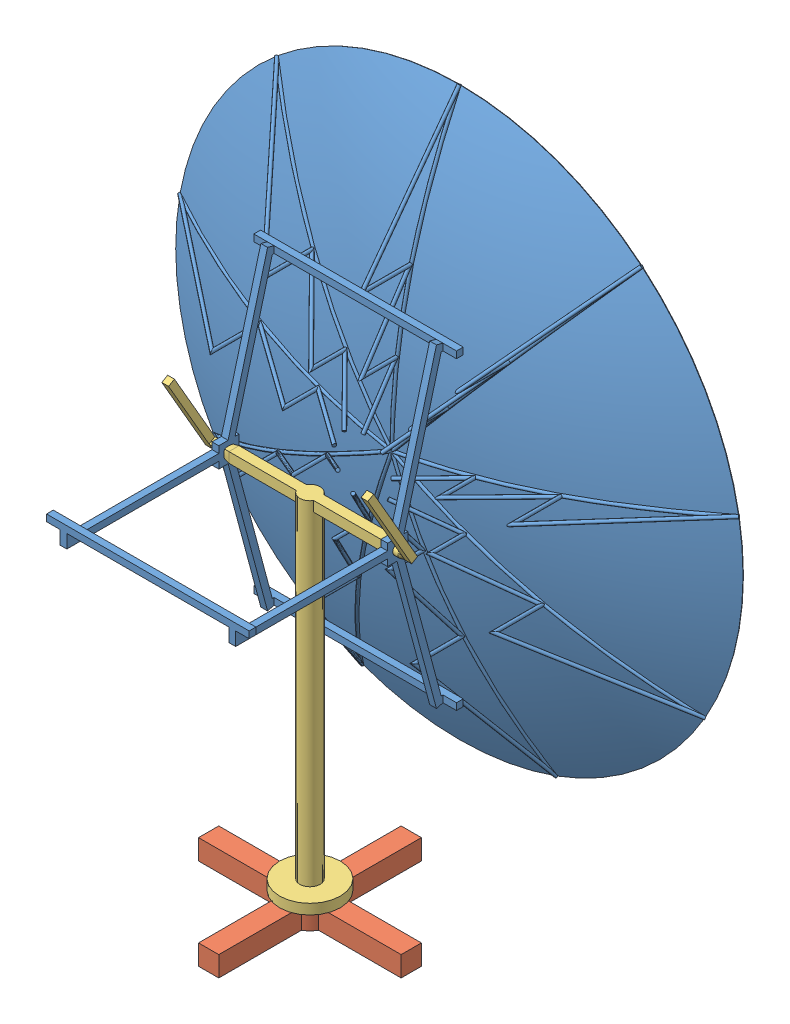
SolidWorks assembly Assembly, configuration Default. Lengths in mm.
Overall size (8534.4 9692.46 7467.6).
3 component instances, 3 part files, 6 mates.
Components (placement in the parent):
- Dish-1: Dish [Default] x (-1 0 0) z (0 0 -1) size (8534.4 8549.46 7467.6)
- Bottom-1: Bottom [Default] at origin size (3048 304.8 3048)
- Base-2: Base [Default] x (-1 0 0) z (0 0 -1) size (3098.8 6230.65 1136.19)
Mates (geometry in assembly coordinates):
- Coincident3: coincident: point of Dish-1
- Coincident4: coordinate: unknown of Bottom-1
- Concentric2: concentric anti-aligned: circle of Bottom-1; circle of Base-2
- Concentric3: concentric aligned: circle of Dish-1; circle of Base-2
- Angle4: planar angle = 3.141593 rad aligned: plane of Dish-1 through (-1524 254 2336.8) normal (-1 0 0); plane of Bottom-1 through (1524 -5410.2 -152.4) normal (1 0 0)
- Angle7: planar angle = 1.047198 rad anti-aligned: plane of Base-2 through (-1549.4 -69.3941 18.5941) normal (0 -0.5 0.866025); plane of Dish-1 through (-1320.8 50.8 0) normal (0 1 0)
